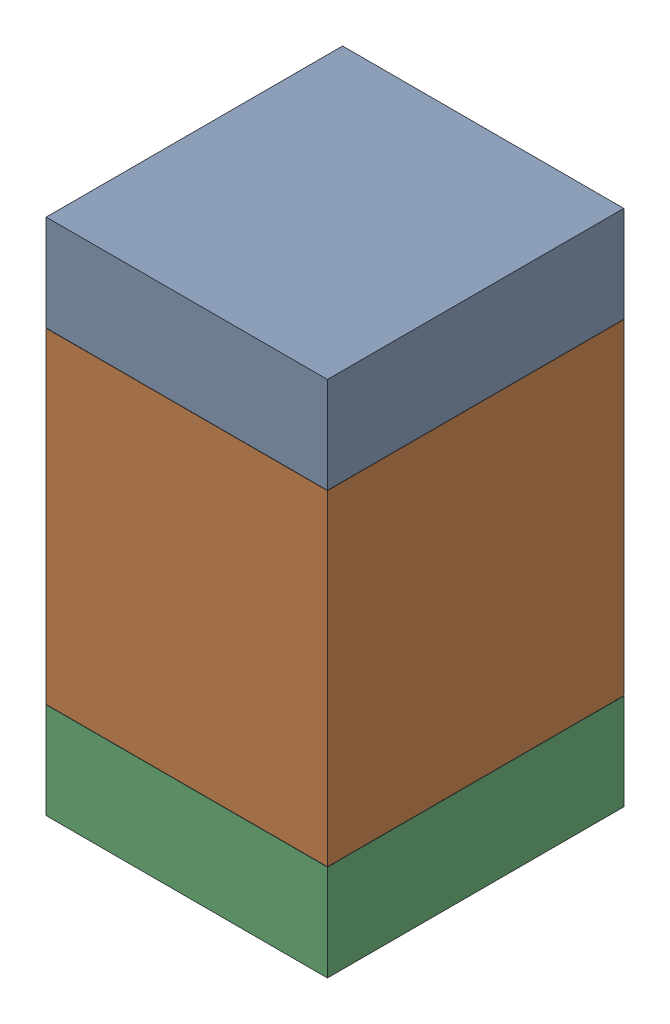
SolidWorks assembly C10, configuration Default. Lengths in mm.
Overall size (0.95 1.75 1).
6 component instances, 2 part files, 0 mates.
Components (placement in the parent):
- 6575495072-1: 6575495072 [Default] at (3.048 20.5245 0) size (0.95 0.32 1)
  - Extruded_6-1: Extruded_6 [Default] at origin size (0.95 0.32 1)
- 6575494912-1: 6575494912 [Default] at (3.048 19.812 0) size (0.95 1.1 1)
  - Extruded_7-1: Extruded_7 [Default] at origin size (0.95 1.1 1)
- 6575495072-2: 6575495072 [Default] at (3.048 19.0995 0) size (0.95 0.32 1)
  - Extruded_6-1: Extruded_6 [Default] at origin size (0.95 0.32 1)
